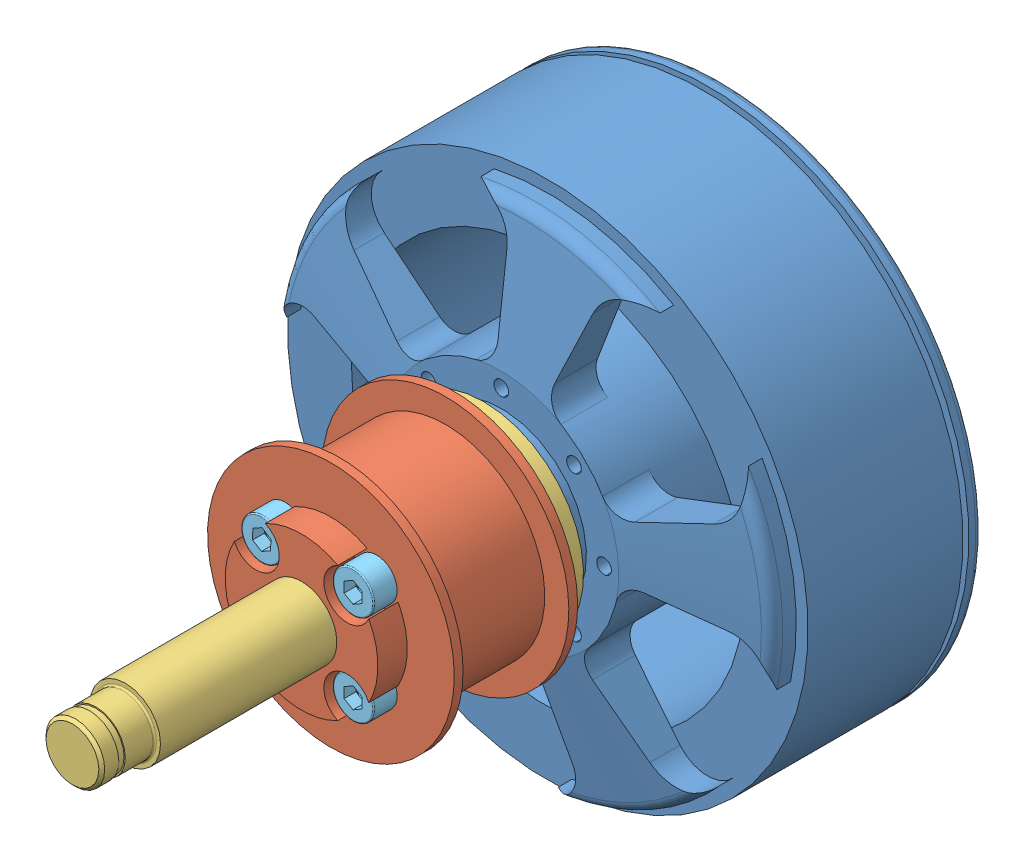
SolidWorks assembly Long Motor Assembly, configuration Default. Lengths in mm.
Overall size (125.3 125.3 113).
11 component instances, 5 part files, 17 mates.
Components (placement in the parent):
- T-Motor U10 KV80-1: T-Motor U10 KV80 [Default] at (50.6204 137.0959 94.3778) x (0.707107 -0.707107 0) z (0 0 1) size (88.6 88.6 43)
- Timing Belt Pulley-1: Timing Belt Pulley [Default] at (50.6204 137.0959 142.3778) x (-0.707107 0.707107 0) z (0 0 -1) size (42 42 26)
- Motor Shaft Long-1: Motor Shaft Long [Default] at (50.6204 137.0959 137.3778) x (0 -1 0) z (0 0 1) size (34 34 90)
- ISO 10642 - M4 x 12 - 12C-9: ISO 10642 - M4 x 12 - 12C [ISO 10642 - M4 x 12 - 12C] at (50.6204 148.5959 142.3578) x (0 0 -1) z (0.997572 0.069644 0) size (12 7.53 7.53)
- ISO 10642 - M4 x 12 - 12C-10: ISO 10642 - M4 x 12 - 12C [ISO 10642 - M4 x 12 - 12C] at (62.1204 137.0959 142.3578) x (0 0 -1) z (1 0 0) size (12 7.53 7.53)
- ISO 10642 - M4 x 12 - 12C-11: ISO 10642 - M4 x 12 - 12C [ISO 10642 - M4 x 12 - 12C] at (39.1204 137.0959 142.3578) x (0 0 -1) z (1 0 0) size (12 7.53 7.53)
- ISO 10642 - M4 x 12 - 12C-12: ISO 10642 - M4 x 12 - 12C [ISO 10642 - M4 x 12 - 12C] at (50.6204 125.5959 142.3578) x (0 0 -1) z (1 0 0) size (12 7.53 7.53)
- ISO 4762 M4 x 25 - 25C-2: ISO 4762 M4 x 25 - 25C [PreviewCfg] at (58.3986 144.8741 167.3778) x (0 0 -1) z (1 0 0) size (29 7 7)
- ISO 4762 M4 x 25 - 25C-4: ISO 4762 M4 x 25 - 25C [ISO 4762 M4 x 25 - 25C] at (42.8422 144.8741 167.3778) x (0 0 -1) z (0.999681 -0.025261 0) size (29 7 7)
- ISO 4762 M4 x 25 - 25C-6: ISO 4762 M4 x 25 - 25C [ISO 4762 M4 x 25 - 25C] at (42.8422 129.3178 167.3778) x (0 0 -1) z (1 0 0) size (29 7 7)
- ISO 4762 M4 x 25 - 25C-8: ISO 4762 M4 x 25 - 25C [ISO 4762 M4 x 25 - 25C] at (58.3986 129.3178 167.3778) x (0 0 -1) z (1 0 0) size (29 7 7)
Mates (geometry in assembly coordinates):
- Concentric5: concentric: cylinder of T-Motor U10 KV80-1 through (50.6204 137.0959 112.3778) axis (0 0 1) radius 5.25; cylinder of Timing Belt Pulley-1 through (50.6204 137.0959 142.3778) axis (0 0 1) radius 6
- Concentric26: concentric: cylinder of T-Motor U10 KV80-1 through (50.6204 137.0959 112.3778) axis (0 0 1) radius 5.25; cylinder of Motor Shaft Long-1 through (50.6204 137.0959 117.3778) axis (0 0 1) radius 5.2
- Concentric27: concentric: cylinder of T-Motor U10 KV80-1 through (50.6204 148.5959 137.3778) axis (0 0 1) radius 1.65; cylinder of Motor Shaft Long-1 through (50.6204 148.5959 142.3778) axis (0 0 1) radius 2
- Coincident10: coincident: plane of T-Motor U10 KV80-1 through (60.8734 147.349 137.3778) normal (0 0 1); plane of Motor Shaft Long-1 through (50.6204 137.0959 137.3778) normal (0 0 -1)
- Coincident15: coincident: plane of Timing Belt Pulley-1 through (65.4696 151.9452 142.3778) normal (0 0 -1); plane of Motor Shaft Long-1 through (50.6204 137.0959 142.3778) normal (0 0 1)
- Coincident16: coincident: plane of Timing Belt Pulley-1 through (59.8128 146.2883 163.3778) normal (0 0 1); plane of ISO 4762 M4 x 25 - 25C-2 through (58.3986 148.3741 163.3778) normal (0 0 -1)
- Coincident17: coincident: plane of Timing Belt Pulley-1 through (59.8128 146.2883 163.3778) normal (0 0 1); plane of ISO 4762 M4 x 25 - 25C-4 through (42.9306 148.373 163.3778) normal (0 0 -1)
- Coincident181: coincident: plane of Timing Belt Pulley-1 through (59.8128 146.2883 163.3778) normal (0 0 1); plane of ISO 4762 M4 x 25 - 25C-6 through (42.8422 132.8178 163.3778) normal (0 0 -1)
- Coincident191: coincident: plane of Timing Belt Pulley-1 through (59.8128 146.2883 163.3778) normal (0 0 1); plane of ISO 4762 M4 x 25 - 25C-8 through (58.3986 132.8178 163.3778) normal (0 0 -1)
- Concentric4648783: concentric: cylinder of Timing Belt Pulley-1 through (58.3986 144.8741 168.3778) axis (0 0 1) radius 2; cylinder of ISO 4762 M4 x 25 - 25C-2 through (58.3986 144.8741 199.1278) axis (0 0 1) radius 2
- Concentric4648784: concentric: cylinder of Timing Belt Pulley-1 through (42.8422 144.8741 168.3778) axis (0 0 1) radius 2; cylinder of ISO 4762 M4 x 25 - 25C-4 through (42.8422 144.8741 199.1278) axis (0 0 1) radius 2
- Concentric4648785: concentric: cylinder of Timing Belt Pulley-1 through (42.8422 129.3178 168.3778) axis (0 0 1) radius 2; cylinder of ISO 4762 M4 x 25 - 25C-6 through (42.8422 129.3178 199.1278) axis (0 0 1) radius 2
- Concentric4648786: concentric: cylinder of Timing Belt Pulley-1 through (58.3986 129.3178 168.3778) axis (0 0 1) radius 2; cylinder of ISO 4762 M4 x 25 - 25C-8 through (58.3986 129.3178 199.1278) axis (0 0 1) radius 2
- Coincident11: coincident: cone of Motor Shaft Long-1 through (50.6204 148.5959 142.3778) axis (0 0 -1); cone of ISO 10642 - M4 x 12 - 12C-9 through (50.6204 148.5959 141.6428) axis (0 0 -1)
- Coincident121: coincident: cone of Motor Shaft Long-1 through (62.1204 137.0959 142.3778) axis (0 0 -1); cone of ISO 10642 - M4 x 12 - 12C-10 through (62.1204 137.0959 141.6428) axis (0 0 -1)
- Coincident131: coincident: cone of Motor Shaft Long-1 through (39.1204 137.0959 142.3778) axis (0 0 -1); cone of ISO 10642 - M4 x 12 - 12C-11 through (39.1204 137.0959 141.6428) axis (0 0 -1)
- Coincident141: coincident: cone of Motor Shaft Long-1 through (50.6204 125.5959 142.3778) axis (0 0 -1); cone of ISO 10642 - M4 x 12 - 12C-12 through (50.6204 125.5959 141.6428) axis (0 0 -1)
